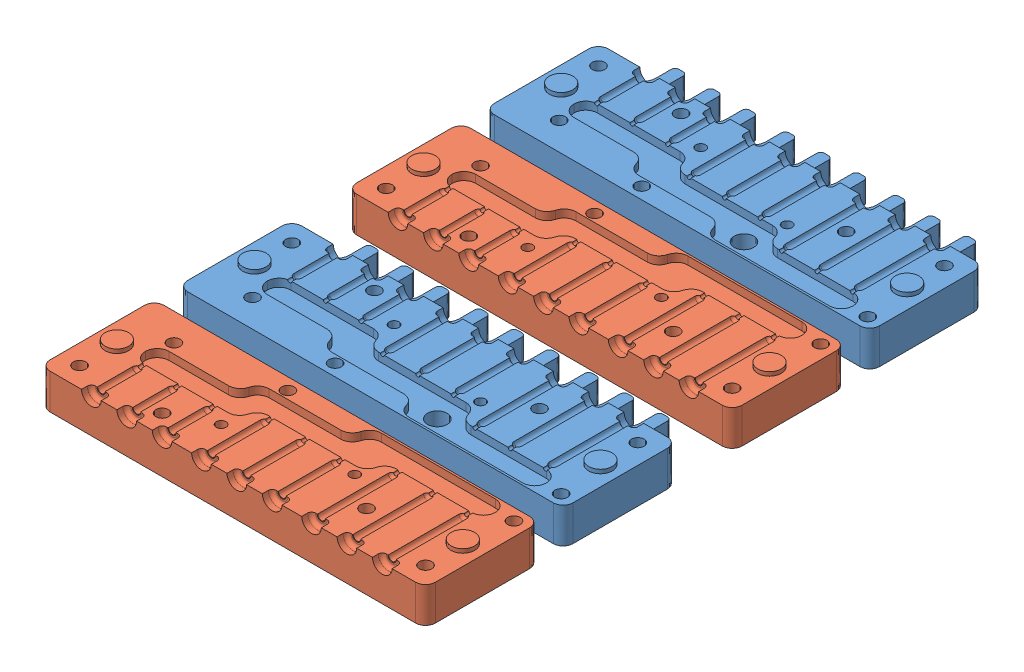
SolidWorks assembly Pt100-Gussformen, configuration Standard. Lengths in mm.
Overall size (98 10 150).
4 component instances, 2 part files, 0 mates.
Components (placement in the parent):
- Pt100-Gussform-SchaleA-1: Pt100-Gussform-SchaleA [Standard] at (-59.4735 -10.4138 12.5) size (98 10 37)
- SpiegelnPt100-Gussform-SchaleA-2: SpiegelnPt100-Gussform-SchaleA [Standard] at (-59.4735 -10.4138 18.5) size (98 10 29)
- Pt100-Gussform-SchaleA-2: Pt100-Gussform-SchaleA [Standard] at (-59.4735 -10.4138 -65.5) size (98 10 37)
- SpiegelnPt100-Gussform-SchaleA-3: SpiegelnPt100-Gussform-SchaleA [Standard] at (-59.4735 -10.4138 -59.5) size (98 10 29)
